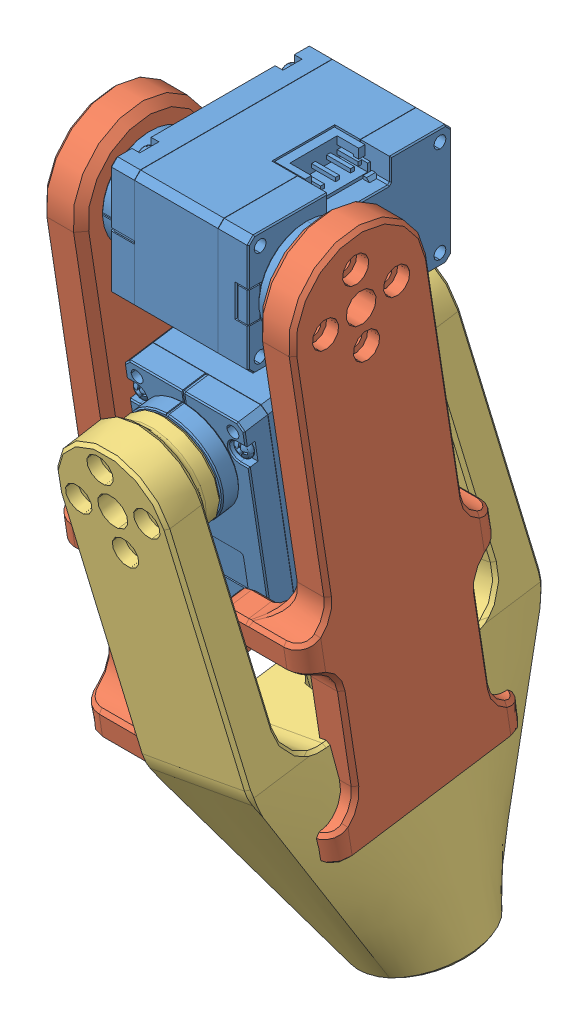
SolidWorks assembly 0200-A-2DOF Arm 330, configuration Default. Lengths in mm.
5 component instances, 3 part files, 13 mates.
Components (placement in the parent):
- DYNAMIXEL XL-330-1: DYNAMIXEL XL-330 [Default] x (0 -1 0) z (-1 0 0) size (20 34 29.02)
- 0200-P-01-Pitch Arm_330-1: 0200-P-01-Pitch Arm_330 [Default] at (-6.5 0 0) x (-1 0 0) z (0 0.988391 0.151932) size (15.23 33.16 89.42)
- 0200-P-01-Pitch Arm_330-2: 0200-P-01-Pitch Arm_330 [Default] at (22.5 0 0) x (1 0 0) z (0 0.988391 0.151932) size (15.23 33.16 89.42)
- DYNAMIXEL XL-330-2: DYNAMIXEL XL-330 [Default] at (8 -26.9995 3.9437) x (1 0 0) z (0 -0.151932 0.988391) size (20 34 29.02)
- 0200-P-02-Roll Arm 330-1: 0200-P-02-Roll Arm 330 [Default] at (8 -28.5948 14.3218) x (0 -0.151932 0.988391) z (-0.205833 0.967227 0.148678) size (49.7 19.07 86.79)
Mates (geometry in assembly coordinates):
- Coincident2: coincident anti-aligned: plane of DYNAMIXEL XL-330-1 through (0 0 0) normal (0 -1 0)
- Coincident3: coincident anti-aligned: plane of DYNAMIXEL XL-330-1 through (0 0 0) normal (-1 0 0)
- Coincident4: coincident aligned: plane of DYNAMIXEL XL-330-1 through (0 0 0) normal (0 0 1)
- Concentric1: concentric anti-aligned: cylinder of DYNAMIXEL XL-330-1 through (-3.6 0 0) axis (-1 0 0) radius 8; cylinder of 0200-P-01-Pitch Arm_330-1 through (-12.85 0 0) axis (1 0 0) radius 2.5
- Coincident5: coincident anti-aligned: plane of DYNAMIXEL XL-330-1 through (-6.5 0 0) normal (-1 0 0); plane of 0200-P-01-Pitch Arm_330-1 through (-6.5 0 0) normal (1 0 0)
- Concentric2: concentric anti-aligned: cylinder of DYNAMIXEL XL-330-1 through (19.6 0 0) axis (1 0 0) radius 8; cylinder of 0200-P-01-Pitch Arm_330-2 through (28.85 0 0) axis (-1 0 0) radius 2.5
- Coincident6: coincident anti-aligned: plane of DYNAMIXEL XL-330-1 through (22.5 0 0) normal (1 0 0); plane of 0200-P-01-Pitch Arm_330-2 through (22.5 0 0) normal (-1 0 0)
- Concentric3: concentric anti-aligned: cylinder of 0200-P-01-Pitch Arm_330-1 through (-12.85 -5.9303 -0.9116) axis (-1 0 0) radius 1.2; cylinder of 0200-P-01-Pitch Arm_330-2 through (28.85 -5.9303 -0.9116) axis (1 0 0) radius 1.2
- Coincident7: coincident anti-aligned: plane of 0200-P-01-Pitch Arm_330-1 through (-6.5 -1.7472 11.3665) normal (0 0.151932 -0.988391); plane of DYNAMIXEL XL-330-2 through (8 -27.5312 7.4031) normal (0 -0.151932 0.988391)
- Parallel1: parallel anti-aligned: plane of 0200-P-01-Pitch Arm_330-1 through (-12.85 0 0) normal (-1 0 0); plane of DYNAMIXEL XL-330-2 through (18 -51.2151 0.2214) normal (1 0 0)
- Concentric5: concentric anti-aligned: cylinder of 0200-P-01-Pitch Arm_330-1 through (0 -20.8901 13.5636) axis (0 -0.151932 0.988391) radius 1.2; cylinder of DYNAMIXEL XL-330-2 through (0 -19.5865 5.0832) axis (0 0.151932 -0.988391) radius 1
- Concentric6: concentric anti-aligned: cylinder of DYNAMIXEL XL-330-2 through (8 -27.5464 7.5019) axis (0 -0.151932 0.988391) radius 8; cylinder of 0200-P-02-Roll Arm 330-1 through (8 -29.5595 20.5981) axis (0 0.151932 -0.988391) radius 2.5
- Coincident9: coincident anti-aligned: plane of DYNAMIXEL XL-330-2 through (8 -27.987 10.3683) normal (0 -0.151932 0.988391); plane of 0200-P-02-Roll Arm 330-1 through (8 -27.987 10.3683) normal (0 0.151932 -0.988391)
